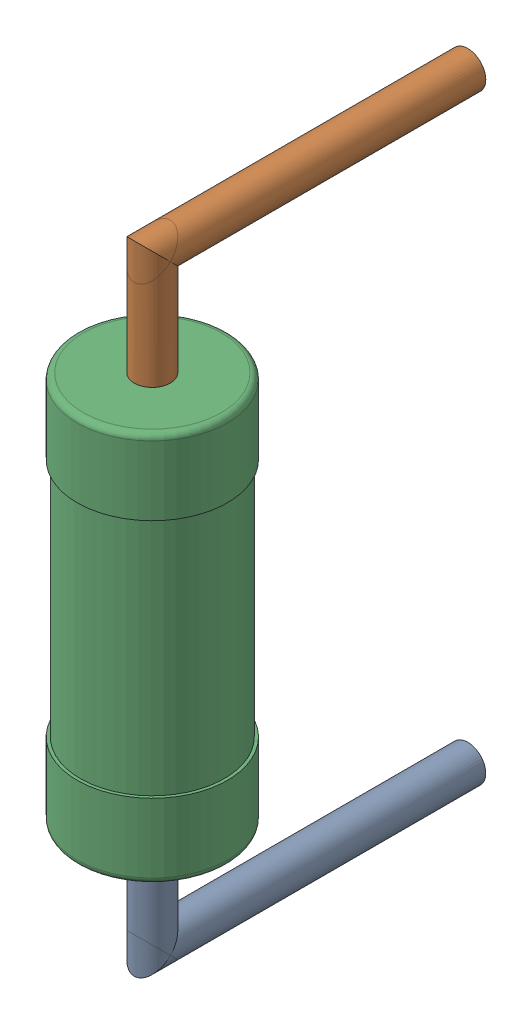
SolidWorks assembly R3.step, configuration Default. Lengths in mm.
Overall size (2.5 10.6 6.5).
3 component instances, 3 part files, 0 mates.
Components (placement in the parent):
- Res_Vishay_BC_Components_MRS25000C1101FCT00_eec.step-1: Res_Vishay_BC_Components_MRS25000C1101FCT00_eec.step [Default] at (25.146 35.814 0) x (0 1 0) z (0 0 1) size (2.05 0.6 5.55)
- Res_Vishay_BC_Components_MRS25000C1101FCT00_eec-2.step-1: Res_Vishay_BC_Components_MRS25000C1101FCT00_eec-2.step [Default] at (25.146 35.814 0) x (0 1 0) z (0 0 1) size (2.05 0.6 5.55)
- Res_Vishay_BC_Components_MRS25000C1101FCT00_eec-3.step-1: Res_Vishay_BC_Components_MRS25000C1101FCT00_eec-3.step [Default] at (25.146 35.814 0) x (0 1 0) z (0 0 1) size (6.5 2.5 2.5)
